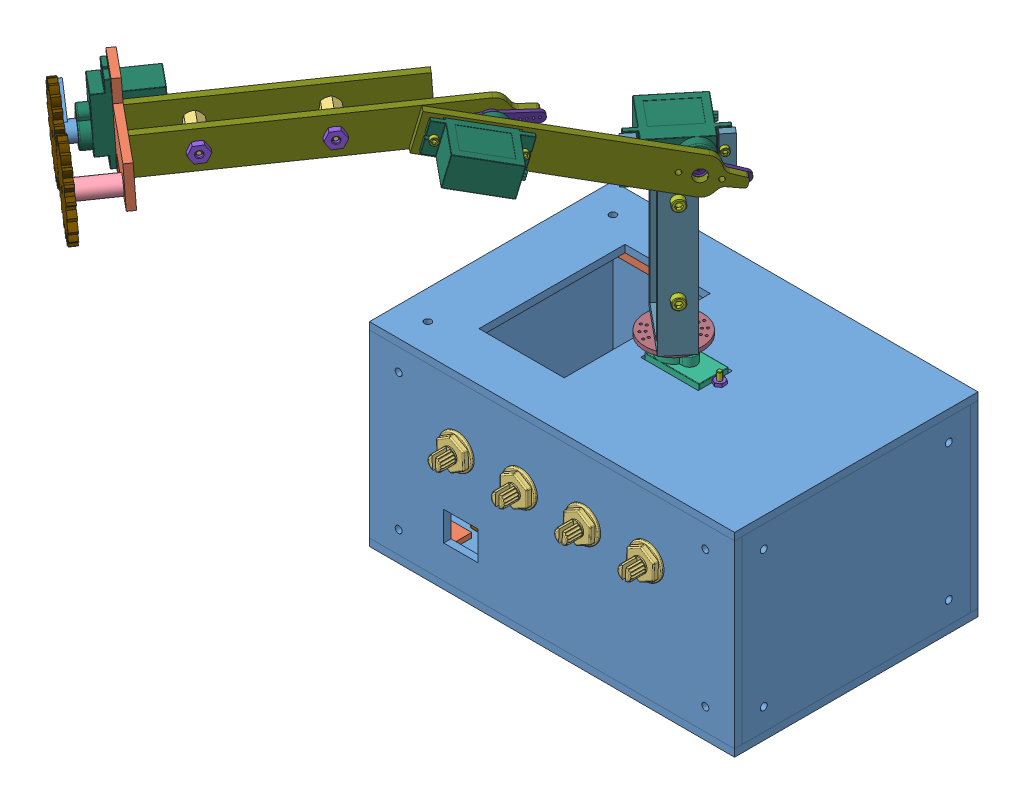
SolidWorks assembly baseAssem, configuration Default. Lengths in mm.
Overall size (216.34 190.48 226.77).
72 component instances, 22 part files, 144 mates.
Components (placement in the parent):
- base-2: base [bottom] at (55.526 72.3187 118.4129) size (150 3 100)
- base-3: base [top] at (55.526 149.3187 118.4129) size (150 3 100)
- base-4: base [right] at (55.526 112.3187 165.4129) x (1 0 0) z (0 -1 0) size (150 3 74)
- base-5: base [left] at (55.526 112.3187 68.4129) x (-1 0 0) z (0 1 0) size (150 3 74)
- base-6: base [back] at (-16.474 112.3187 118.4129) x (0 0 -1) z (0 1 0) size (94 3 74)
- corner-1: corner [Default] at (-7.474 131.3187 156.4129) x (0 0 1) z (-1 0 0) size (18 18 18)
- corner-3: corner [Default] at (1.526 84.3187 156.4129) x (0 0 1) z (0 -1 0) size (18 18 18)
- corner-4: corner [Default] at (-7.474 93.3187 80.4129) x (0 0 -1) z (-1 0 0) size (18 18 18)
- corner-8: corner [Default] at (-7.474 140.3187 89.4129) x (0 1 0) z (-1 0 0) size (18 18 18)
- base-7: base [front] at (127.526 112.3187 118.4129) x (0 0 1) z (0 1 0) size (94 3 74)
- Panel Mount 10k Potentiometer-1: Panel Mount 10k Potentiometer [Default] at (16.526 124.3187 161.9129) x (0 0 1) z (-0.999338 -0.036385 0) size (23.57 25.5 17)
- Panel Mount 10k Potentiometer-2: Panel Mount 10k Potentiometer [Default] at (42.526 124.3187 161.9129) x (0 0 1) z (-0.999906 0.013744 0) size (23.57 25.5 17)
- Panel Mount 10k Potentiometer-3: Panel Mount 10k Potentiometer [Default] at (68.526 124.3187 161.9129) x (0 0 1) z (-0.998975 0.045273 0) size (23.57 25.5 17)
- Panel Mount 10k Potentiometer-4: Panel Mount 10k Potentiometer [Default] at (94.526 124.3187 161.9129) x (0 0 1) z (-0.999254 0.038611 0) size (23.57 25.5 17)
- Panel Mount LED-1: Panel Mount LED [Default] at (50.526 112.3187 78.4129) x (0.923439 -0.383746 0) z (0.383746 0.923439 0) size (11.13 16 10.04)
- Panel Mount SPDT-1: Panel Mount SPDT [Default] at (70.526 112.3187 83.8429) x (-1 0 0) z (0 -1 0) size (8 31.74 12.7)
- Micro Servo FS90R Continuous - Copy-1: Micro Servo FS90R Continuous - Copy [Valor predeterminado] at (60.771 147.3187 118.4129) size (32 29 12)
- socket head cap screw_ai-25: socket head cap screw_ai [HX-SHCS 0.073-72x0.375x0.375-N] at (47.146 145.4645 118.4129) x (0 1 0) z (-0.929485 0 -0.368859) size (11.38 3 3)
- socket head cap screw_ai-26: socket head cap screw_ai [HX-SHCS 0.073-72x0.375x0.375-N] at (74.396 145.4645 118.4129) x (0 1 0) z (-0.215216 0 0.976566) size (11.38 3 3)
- machine screw nut hex_ai-1: machine screw nut hex_ai [MSHXNUT 0.073-72-S-N] at (74.396 153.5887 118.4129) x (-0.435877 0 0.900006) z (0 1 0) size (3.96 4.58 1.27)
- machine screw nut hex_ai-2: machine screw nut hex_ai [MSHXNUT 0.073-72-S-N] at (47.146 153.5887 118.4129) x (0.391838 0 0.920034) z (0 1 0) size (3.96 4.58 1.27)
- ArduinoUno-1: ArduinoUno [Default] at (29.676 88.0187 119.4129) x (0 0 -1) z (1 0 0) size (74.8 12.1 53.3)
- Arduino Prototyping Shield-1: Arduino Prototyping Shield [Default] at (30.976 97.6187 118.1031) x (0 0 1) z (-1 0 0) size (68 18.92 56)
- MiniBreadboard-Simple-1: MiniBreadboard-Simple [Default] at (30.276 99.2487 122.3031) x (-1 0 0) z (0 0 -1) size (34.6 8.15 45.6)
- 25x.5 Aluminum Hex Female Female Standoff-1: 25x.5 Aluminum Hex Female Female Standoff [Default] at (48.726 81.6687 86.0129) x (0.839669 0 0.543098) z (0 1 0) size (6.35 8.06 12.7)
- 25x.5 Aluminum Hex Female Female Standoff-2: 25x.5 Aluminum Hex Female Female Standoff [Default] at (5.526 81.6687 136.8129) x (0.967511 0 -0.252828) z (0 -1 0) size (6.35 8.06 12.7)
- 25x.5 Aluminum Hex Female Female Standoff-3: 25x.5 Aluminum Hex Female Female Standoff [Default] at (20.826 81.6687 86.0129) x (0.85033 0 -0.52625) z (0 1 0) size (6.35 8.06 12.7)
- 25x.5 Aluminum Hex Female Female Standoff-4: 25x.5 Aluminum Hex Female Female Standoff [Default] at (53.826 81.6687 138.4129) x (0.990977 0 0.134031) z (0 -1 0) size (6.35 8.06 12.7)
- bottom servo assem-1: bottom servo assem [Default] at (59.6282 148.85 98.1163) x (0.770206 0 0.637795) z (-0.637795 0 0.770206) size (36.89 82.63 34.06) (flexible)
  - Micro Servo Horn Round-1: Micro Servo Horn Round [Default] at (9.7817 11.4557 18.2521) size (23.65 4.35 23.65)
  - bottom servo arm-1: bottom servo arm [Default] at (9.7714 16.0686 18.2394) x (0.999997 0 -0.002296) z (-0.002296 0 -0.999997) size (26 78 34)
  - socket head cap screw_ai-1: socket head cap screw_ai [HX-SHCS 0.112-40x0.5x0.5-N] at (25.6162 33.0686 18.203) x (-0.999997 0 0.002296) z (-0.000065 -0.999594 -0.028493) size (15.54 4.65 4.65)
  - socket head cap screw_ai-2: socket head cap screw_ai [HX-SHCS 0.112-40x0.5x0.5-N] at (25.6162 68.0686 18.203) x (-0.999997 0 0.002296) z (-0.000065 -0.999594 -0.028493) size (15.54 4.65 4.65)
  - 25x.5 Aluminum Hex Female Female Standoff-1: 25x.5 Aluminum Hex Female Female Standoff [Default] at (9.7714 68.0686 18.2394) x (-0.002123 -0.380865 -0.924628) z (0.999997 0 -0.002296) size (6.35 8.06 12.7)
  - 25x.5 Aluminum Hex Female Female Standoff-2: 25x.5 Aluminum Hex Female Female Standoff [Default] at (9.7714 33.0686 18.2394) x (-0.001939 -0.535745 -0.844378) z (0.999997 0 -0.002296) size (6.35 8.06 12.7)
  - Micro Servo SG92R 180-1: Micro Servo SG92R 180 [Valor predeterminado] at (17.7714 85.5949 18.221) x (0.002296 0 0.999997) z (0 1 0) size (32 29 12)
  - socket head cap screw_ai-3: socket head cap screw_ai [HX-SHCS 0.112-40x0.5x0.5-N] at (-6.0733 68.0686 18.2758) x (0.999997 0 -0.002296) z (-0.000307 -0.991051 -0.133483) size (15.54 4.65 4.65)
  - socket head cap screw_ai-4: socket head cap screw_ai [HX-SHCS 0.112-40x0.5x0.5-N] at (-6.0733 33.0686 18.2758) x (0.999997 0 -0.002296) z (-0.000307 -0.991051 -0.133483) size (15.54 4.65 4.65)
  - socket head cap screw_ai-5: socket head cap screw_ai [HX-SHCS 0.073-72x0.375x0.375-N] at (24.6569 85.5949 31.8303) x (-0.999997 0 0.002296) z (-0.002286 -0.096256 -0.995354) size (11.38 3 3)
  - socket head cap screw_ai-6: socket head cap screw_ai [HX-SHCS 0.073-72x0.375x0.375-N] at (24.5943 85.5949 4.5803) x (-0.999997 0 0.002296) z (0.000316 0.990504 0.137486) size (11.38 3 3)
  - machine screw nut hex_ai-3: machine screw nut hex_ai [MSHXNUT 0.073-72-S-N] at (17.8027 85.5949 31.846) x (-0.002207 -0.276755 -0.960938) z (0.999997 0 -0.002296) size (3.96 4.58 1.27)
  - machine screw nut hex_ai-4: machine screw nut hex_ai [MSHXNUT 0.073-72-S-N] at (17.7401 85.5949 4.5961) x (-0.001605 -0.71523 -0.698887) z (0.999997 0 -0.002296) size (3.96 4.58 1.27)
- machine screw nut hex_ai-3: machine screw nut hex_ai [MSHXNUT 0.073-72-S-N] at (51.25 166.1887 114.8762) x (1 0 0) z (0 1 0) size (3.96 4.58 1.27)
- machine screw nut hex_ai-4: machine screw nut hex_ai [MSHXNUT 0.073-72-S-N] at (59.7924 166.1887 121.917) x (1 0 0) z (0 1 0) size (3.96 4.58 1.27)
- socket head cap screw_ai-27: socket head cap screw_ai [HX-SHCS 0.073-72x0.375x0.375-N] at (59.7924 158.4516 121.917) x (0 1 0) z (0.579913 0 0.814678) size (11.38 3 3)
- socket head cap screw_ai-28: socket head cap screw_ai [HX-SHCS 0.073-72x0.375x0.375-N] at (51.25 158.4516 114.8762) x (0 1 0) z (-0.855432 0 -0.517915) size (11.38 3 3)
- corner-11: corner [Default] at (109.526 140.3187 80.4129) x (0 1 0) z (0 0 -1) size (18 18 18)
- corner-12: corner [Default] at (109.526 84.3187 156.4129) x (0 -1 0) z (0 0 1) size (18 18 18)
- corner-13: corner [Default] at (118.526 131.3187 156.4129) size (18 18 18)
- corner-14: corner [Default] at (109.526 84.3187 80.4129) x (0 0 -1) z (0 -1 0) size (18 18 18)
- second servo arm-1: second servo arm [Default] at (54.5607 243.1953 155.2982) x (-0.616355 0.246769 0.747805) z (0.156951 0.969074 -0.190424) size (100 3 15)
- Micro Servo Horn Double Arm-1: Micro Servo Horn Double Arm [Default] at (75.1551 234.4449 127.7758) x (-0.616511 0.245803 0.747994) z (0.156336 0.96932 -0.189678) size (32.23 4.23 7.24)
- Micro Servo SG92R 180-1: Micro Servo SG92R 180 [Valor predeterminado] at (38.9269 250.9994 182.1276) x (-0.616355 0.246769 0.747805) z (-0.156951 -0.969074 0.190424) size (32 29 12)
- socket head cap screw_ai-29: socket head cap screw_ai [HX-SHCS 0.073-72x0.375x0.375-N] at (32.114 254.2999 193.3088) x (-0.771669 0 -0.636024) z (0.582813 0.400408 -0.707109) size (11.38 3 3)
- machine screw nut hex_ai-5: machine screw nut hex_ai [MSHXNUT 0.073-72-S-N] at (26.8248 254.2999 188.9494) x (-0.062279 -0.995194 0.075561) z (0.771669 0 0.636024) size (3.96 4.58 1.27)
- socket head cap screw_ai-30: socket head cap screw_ai [HX-SHCS 0.073-72x0.375x0.375-N] at (48.9096 247.5755 172.9311) x (-0.771669 0 -0.636024) z (-0.301428 -0.880565 0.365714) size (11.38 3 3)
- machine screw nut hex_ai-6: machine screw nut hex_ai [MSHXNUT 0.073-72-S-N] at (43.6205 247.5755 168.5717) x (0.611181 -0.276759 -0.741527) z (0.771669 0 0.636024) size (3.96 4.58 1.27)
- Micro Servo Horn Double Arm-2: Micro Servo Horn Double Arm [Default] at (32.0414 249.7038 169.8594) x (-0.634939 -0.058392 0.770352) z (0.037139 -0.998294 -0.04506) size (32.23 4.23 7.24)
- second servo arm-3: second servo arm [third servo arm] at (8.2998 247.593 196.1284) x (-0.634902 -0.059388 0.770307) z (0.037772 -0.998235 -0.045828) size (120 3 15)
- root_gear-1: root_gear [other robot gear] at (-66.1465 236.144 247.7741) x (-0.605578 0.657397 -0.448447) z (0.479765 0.751201 0.453346) size (32.73 3 32.73)
- Micro Servo Horn Single Arm-1: Micro Servo Horn Single Arm [Default] at (-65.1225 236.2398 246.5317) x (0.605578 -0.657397 0.448447) z (-0.479765 -0.751201 -0.453346) size (19.74 4.23 7.24)
- Micro Servo SG92R 180-2: Micro Servo SG92R 180 [Valor predeterminado] at (-56.9933 242.2594 236.6688) x (-0.037772 0.998235 0.045828) z (0.771669 0 0.636024) size (32 29 12)
- second servo arm-4: second servo arm [fourth servo supporter] at (-6.1304 247.593 184.2348) x (-0.634902 -0.059388 0.770307) z (-0.037772 0.998235 0.045828) size (90 3 15)
- socket head cap screw_ai-31: socket head cap screw_ai [HX-SHCS 0.112-40x0.375x0.375-N] at (-14.6746 246.9991 190.1285) x (0.771669 0 0.636024) z (0.08876 -0.990214 -0.10769) size (12.37 4.65 4.65)
- socket head cap screw_ai-34: socket head cap screw_ai [HX-SHCS 0.112-40x0.375x0.375-N] at (-40.0707 244.6236 220.9407) x (0.771669 0 0.636024) z (0.384692 -0.796349 -0.466735) size (12.37 4.65 4.65)
- gear support-1: gear support [Default] at (-43.3206 242.4376 244.0572) x (0.771669 0 0.636024) z (0.037772 -0.998235 -0.045828) size (46 3 35)
- 25x.5 Aluminum Hex Male Female Standoff-1: 25x.5 Aluminum Hex Male Female Standoff [Default] at (-30.6604 244.6236 228.6969) x (-0.245877 0.922254 0.298315) z (-0.771669 0 -0.636024) size (6.35 8.06 17.4)
- 25x.5 Aluminum Hex Male Female Standoff-2: 25x.5 Aluminum Hex Male Female Standoff [Default] at (-5.2643 246.9991 197.8846) x (-0.257451 0.914413 0.312358) z (-0.771669 0 -0.636024) size (6.35 8.06 17.4)
- machine screw nut hex_ai-7: machine screw nut hex_ai [MSHXNUT 0.112-40-S-N] at (1.9508 246.9991 203.8315) x (0.516896 0.582684 -0.627135) z (-0.771669 0 -0.636024) size (6.35 7.33 2.49)
- machine screw nut hex_ai-8: machine screw nut hex_ai [MSHXNUT 0.112-40-S-N] at (-23.4453 244.6236 234.6438) x (0.516896 0.582684 -0.627135) z (-0.771669 0 -0.636024) size (6.35 7.33 2.49)
- root_gear-2: root_gear [other robot gear] at (-43.3106 236.4934 266.6229) x (0.649947 0.497985 0.574091) z (0.417695 -0.86515 0.277573) size (32.73 3 32.73)
- 3D printed standoff-1: 3D printed standoff [Default] at (-43.3112 236.4933 266.6235) x (0.770009 0.032837 0.637188) z (-0.634902 -0.059388 0.770307) size (7 12.18 14.73)
Mates (geometry in assembly coordinates):
- Coincident1: coincident anti-aligned: plane of base-2 through (55.526 75.3187 118.4129) normal (0 1 0); plane of base-4 through (130.526 75.3187 168.4129) normal (0 -1 0)
- Coincident2: coincident aligned: line of base-2 through (-19.474 75.3187 168.4129) axis (1 0 0); line of base-4 through (-19.474 75.3187 168.4129) axis (1 0 0)
- Coincident3: coincident aligned: line of base-2 through (130.526 75.3187 168.4129) axis (0 0 -1); line of base-4 through (130.526 75.3187 168.4129) axis (0 0 -1)
- Coincident4: coincident anti-aligned: plane of base-2 through (55.526 75.3187 118.4129) normal (0 1 0); plane of base-5 through (-19.474 75.3187 71.4129) normal (0 -1 0)
- Coincident6: coincident anti-aligned: line of base-2 through (130.526 75.3187 68.4129) axis (-1 0 0); line of base-5 through (-19.474 75.3187 68.4129) axis (1 0 0)
- Coincident7: coincident aligned: line of base-2 through (130.526 75.3187 168.4129) axis (0 0 -1); line of base-5 through (130.526 75.3187 71.4129) axis (0 0 -1)
- Coincident12: coincident anti-aligned: plane of base-2 through (55.526 75.3187 118.4129) normal (0 1 0); plane of base-6 through (-19.474 75.3187 71.4129) normal (0 -1 0)
- Coincident13: coincident anti-aligned: plane of base-5 through (55.526 112.3187 71.4129) normal (0 0 1); plane of base-6 through (-19.474 149.3187 71.4129) normal (0 0 -1)
- Coincident14: coincident aligned: line of base-2 through (-19.474 75.3187 68.4129) axis (0 0 1); line of base-6 through (-19.474 75.3187 71.4129) axis (0 0 1)
- Coincident15: coincident anti-aligned: plane of base-3 through (55.526 149.3187 118.4129) normal (0 -1 0); plane of base-6 through (-19.474 149.3187 71.4129) normal (0 1 0)
- Coincident16: coincident anti-aligned: line of base-3 through (-19.474 149.3187 168.4129) axis (1 0 0); line of base-4 through (130.526 149.3187 168.4129) axis (-1 0 0)
- Coincident18: coincident anti-aligned: plane of base-4 through (55.526 112.3187 165.4129) normal (0 0 -1); plane of corner-1 through (-16.474 149.3187 165.4129) normal (0 0 1)
- Coincident19: coincident anti-aligned: plane of base-6 through (-16.474 112.3187 118.4129) normal (1 0 0); plane of corner-1 through (-16.474 149.3187 147.4129) normal (-1 0 0)
- Coincident20: coincident anti-aligned: plane of base-3 through (55.526 149.3187 118.4129) normal (0 -1 0); plane of corner-1 through (-7.474 149.3187 156.4129) normal (0 1 0)
- Coincident21: coincident anti-aligned: plane of base-5 through (55.526 112.3187 71.4129) normal (0 0 1); plane of corner-8 through (-7.474 140.3187 71.4129) normal (0 0 -1)
- Coincident22: coincident anti-aligned: plane of base-3 through (55.526 149.3187 118.4129) normal (0 -1 0); plane of corner-8 through (-16.474 149.3187 71.4129) normal (0 1 0)
- Coincident23: coincident anti-aligned: plane of base-6 through (-16.474 112.3187 118.4129) normal (1 0 0); plane of corner-8 through (-16.474 131.3187 71.4129) normal (-1 0 0)
- Coincident36: coincident anti-aligned: plane of base-5 through (55.526 112.3187 71.4129) normal (0 0 1); plane of corner-4 through (-16.474 75.3187 71.4129) normal (0 0 -1)
- Coincident37: coincident anti-aligned: plane of base-6 through (-16.474 112.3187 118.4129) normal (1 0 0); plane of corner-4 through (-16.474 75.3187 89.4129) normal (-1 0 0)
- Coincident38: coincident anti-aligned: plane of base-2 through (55.526 75.3187 118.4129) normal (0 1 0); plane of corner-4 through (-7.474 75.3187 80.4129) normal (0 -1 0)
- Coincident39: coincident anti-aligned: plane of base-6 through (-16.474 112.3187 118.4129) normal (1 0 0); plane of corner-3 through (-16.474 84.3187 156.4129) normal (-1 0 0)
- Coincident40: coincident anti-aligned: plane of base-2 through (55.526 75.3187 118.4129) normal (0 1 0); plane of corner-3 through (-16.474 75.3187 147.4129) normal (0 -1 0)
- Coincident41: coincident anti-aligned: plane of base-4 through (55.526 112.3187 165.4129) normal (0 0 -1); plane of corner-3 through (-16.474 75.3187 165.4129) normal (0 0 1)
- Coincident53: coincident anti-aligned: line of base-3 through (-19.474 149.3187 68.4129) axis (0 0 1); line of base-6 through (-19.474 149.3187 165.4129) axis (0 0 -1)
- Coincident63: coincident anti-aligned: plane of base-4 through (55.526 112.3187 165.4129) normal (0 0 -1); plane of base-7 through (130.526 149.3187 165.4129) normal (0 0 1)
- Coincident70: coincident anti-aligned: plane of base-4 through (55.526 112.3187 168.4129) normal (0 0 1); plane of Panel Mount 10k Potentiometer-1 through (16.526 124.3187 168.4129) normal (0 0 -1)
- Concentric1: concentric anti-aligned: cylinder of base-4 through (16.526 124.3187 158.4129) axis (0 0 1) radius 3.625; circle of Panel Mount 10k Potentiometer-1
- Coincident71: coincident anti-aligned: plane of base-4 through (55.526 112.3187 168.4129) normal (0 0 1); plane of Panel Mount 10k Potentiometer-2 through (42.526 124.3187 168.4129) normal (0 0 -1)
- Concentric2: concentric anti-aligned: circle of base-4; circle of Panel Mount 10k Potentiometer-2
- Coincident72: coincident anti-aligned: plane of base-4 through (55.526 112.3187 168.4129) normal (0 0 1); plane of Panel Mount 10k Potentiometer-3 through (68.526 124.3187 168.4129) normal (0 0 -1)
- Concentric3: concentric anti-aligned: cylinder of base-4 through (68.526 124.3187 158.4129) axis (0 0 1) radius 3.625; circle of Panel Mount 10k Potentiometer-3
- Coincident73: coincident anti-aligned: plane of base-4 through (55.526 112.3187 168.4129) normal (0 0 1); plane of Panel Mount 10k Potentiometer-4 through (94.526 124.3187 168.4129) normal (0 0 -1)
- Concentric4: concentric anti-aligned: cylinder of base-4 through (94.526 124.3187 158.4129) axis (0 0 1) radius 3.625; circle of Panel Mount 10k Potentiometer-4
- Coincident74: coincident anti-aligned: plane of base-5 through (55.526 112.3187 68.4129) normal (0 0 -1); plane of Panel Mount SPDT-1 through (74.526 114.6281 68.4129) normal (0 0 1)
- Concentric5: concentric anti-aligned: cylinder of base-5 through (70.526 112.3187 78.4129) axis (0 0 -1) radius 4; cylinder of Panel Mount SPDT-1 through (70.526 112.3187 66.4129) axis (0 0 1) radius 3.175
- Coincident75: coincident anti-aligned: plane of base-5 through (55.526 112.3187 68.4129) normal (0 0 -1); plane of Panel Mount LED-1 through (55.1623 110.392 68.4129) normal (0 0 1)
- Concentric6: concentric anti-aligned: cylinder of base-5 through (50.526 112.3187 78.4129) axis (0 0 -1) radius 4; cylinder of Panel Mount LED-1 through (50.526 112.3187 78.4129) axis (0 0 1) radius 3.937
- Coincident76: coincident anti-aligned: plane of base-3 through (55.526 149.3187 118.4129) normal (0 -1 0); plane of Micro Servo FS90R Continuous - Copy-1 through (74.396 149.3187 118.4129) normal (0 1 0)
- Concentric7: concentric anti-aligned: circle of base-3; circle of Micro Servo FS90R Continuous - Copy-1
- Concentric8: concentric anti-aligned: circle of base-3; circle of Micro Servo FS90R Continuous - Copy-1
- Concentric9: concentric anti-aligned: cylinder of base-3 through (74.396 142.3187 118.4129) axis (0 1 0) radius 1.25; cylinder of socket head cap screw_ai-26 through (74.396 113.7145 118.4129) axis (0 -1 0) radius 0.9271
- Coincident77: coincident anti-aligned: plane of Micro Servo FS90R Continuous - Copy-1 through (74.396 147.3187 118.4129) normal (0 -1 0); plane of socket head cap screw_ai-26 through (72.9325 147.3187 118.0904) normal (0 1 0)
- Concentric10: concentric anti-aligned: cylinder of base-3 through (47.146 142.3187 118.4129) axis (0 1 0) radius 1.25; cylinder of socket head cap screw_ai-25 through (47.146 113.7145 118.4129) axis (0 -1 0) radius 0.9271
- Coincident78: coincident anti-aligned: plane of Micro Servo FS90R Continuous - Copy-1 through (47.146 147.3187 118.4129) normal (0 -1 0); plane of socket head cap screw_ai-25 through (47.6988 147.3187 117.02) normal (0 1 0)
- Concentric11: concentric anti-aligned: cylinder of socket head cap screw_ai-26 through (74.396 113.7145 118.4129) axis (0 -1 0) radius 0.9271; cylinder of machine screw nut hex_ai-1 through (74.396 152.3187 118.4129) axis (0 1 0) radius 0.7556
- Coincident79: coincident anti-aligned: plane of base-3 through (55.526 152.3187 118.4129) normal (0 1 0); plane of machine screw nut hex_ai-1 through (76.1231 152.3187 114.8468) normal (0 -1 0)
- Concentric12: concentric anti-aligned: cylinder of socket head cap screw_ai-25 through (47.146 113.7145 118.4129) axis (0 -1 0) radius 0.9271; cylinder of machine screw nut hex_ai-2 through (47.146 152.3187 118.4129) axis (0 1 0) radius 0.7556
- Coincident80: coincident anti-aligned: plane of base-3 through (55.526 152.3187 118.4129) normal (0 1 0); plane of machine screw nut hex_ai-2 through (45.5934 152.3187 114.7674) normal (0 -1 0)
- Coincident82: coincident anti-aligned: plane of Arduino Prototyping Shield-1 through (2.976 99.2487 152.1031) normal (0 1 0); plane of MiniBreadboard-Simple-1 through (12.976 99.2487 99.5031) normal (0 -1 0)
- Parallel3: parallel aligned: line of Arduino Prototyping Shield-1 through (2.976 99.2487 152.1031) axis (1 0 0); line of MiniBreadboard-Simple-1 through (12.976 99.2487 145.1031) axis (1 0 0)
- Distance1: distance = 7 mm: line of MiniBreadboard-Simple-1 through (12.976 99.2487 145.1031) axis (1 0 0); line of Arduino Prototyping Shield-1 through (2.976 99.2487 152.1031) axis (1 0 0)
- Distance2: distance = 10 mm: line of MiniBreadboard-Simple-1 through (12.976 99.2487 99.5031) axis (0 0 1); line of Arduino Prototyping Shield-1 through (2.976 99.2487 87.9631) axis (0 0 1)
- Coincident86: coincident anti-aligned: plane of ArduinoUno-1 through (6.676 97.6187 129.9131) normal (0 1 0); plane of Arduino Prototyping Shield-1 through (2.976 97.6187 152.1031) normal (0 -1 0)
- Width1: width anti-aligned: plane of Arduino Prototyping Shield-1 through (5.676 88.8687 89.0131) normal (1 0 0); plane of ArduinoUno-1 through (5.176 88.8687 89.0131) normal (-1 0 0); plane of Arduino Prototyping Shield-1 through (5.926 97.6187 89.7631) normal (-1 0 0); plane of ArduinoUno-1 through (4.926 97.6187 89.7631) normal (1 0 0)
- Width2: width anti-aligned: plane of Arduino Prototyping Shield-1 through (5.176 88.8687 89.0131) normal (0 0 -1); plane of ArduinoUno-1 through (5.176 88.8687 89.5131) normal (0 0 1); plane of Arduino Prototyping Shield-1 through (4.926 97.6187 88.7631) normal (0 0 1); plane of ArduinoUno-1 through (4.926 97.6187 89.7631) normal (0 0 -1)
- Concentric16: concentric aligned: circle of base-2; circle of 25x.5 Aluminum Hex Female Female Standoff-1
- Coincident87: coincident anti-aligned: plane of base-2 through (55.526 75.3187 118.4129) normal (0 1 0); plane of 25x.5 Aluminum Hex Female Female Standoff-1 through (48.726 75.3187 86.0129) normal (0 -1 0)
- Concentric17: concentric aligned: circle of base-2; circle of 25x.5 Aluminum Hex Female Female Standoff-3
- Coincident88: coincident anti-aligned: plane of base-2 through (55.526 75.3187 118.4129) normal (0 1 0); plane of 25x.5 Aluminum Hex Female Female Standoff-3 through (20.826 75.3187 86.0129) normal (0 -1 0)
- Concentric18: concentric anti-aligned: circle of base-2; circle of 25x.5 Aluminum Hex Female Female Standoff-2
- Coincident89: coincident anti-aligned: plane of base-2 through (55.526 75.3187 118.4129) normal (0 1 0); plane of 25x.5 Aluminum Hex Female Female Standoff-2 through (5.526 75.3187 136.8129) normal (0 -1 0)
- Concentric19: concentric anti-aligned: circle of base-2; circle of 25x.5 Aluminum Hex Female Female Standoff-4
- Coincident91: coincident anti-aligned: plane of base-2 through (55.526 75.3187 118.4129) normal (0 1 0); plane of 25x.5 Aluminum Hex Female Female Standoff-4 through (53.826 75.3187 138.4129) normal (0 -1 0)
- Parallel5: parallel aligned: plane of base-2 through (55.526 72.3187 118.4129) normal (0 -1 0); plane of Panel Mount SPDT-1 through (73.956 105.9687 74.9529) normal (0 -1 0)
- Concentric20: concentric aligned: circle of ArduinoUno-1; circle of 25x.5 Aluminum Hex Female Female Standoff-3
- Concentric21: concentric aligned: circle of ArduinoUno-1; circle of 25x.5 Aluminum Hex Female Female Standoff-1
- Coincident93: coincident anti-aligned: plane of ArduinoUno-1 through (3.026 88.0187 86.4129) normal (0 -1 0); plane of 25x.5 Aluminum Hex Female Female Standoff-3 through (20.826 88.0187 86.0129) normal (0 1 0)
- Concentric22: concentric anti-aligned: cylinder of Micro Servo FS90R Continuous - Copy-1 through (55.521 160.3187 118.4129) axis (0 -1 0) radius 2.25; cone of bottom servo assem-1/Micro Servo Horn Round-1 through (55.521 157.8187 118.4129) axis (0 1 0)
- Coincident94: coincident anti-aligned: plane of Micro Servo FS90R Continuous - Copy-1 through (55.521 157.8187 118.4129) normal (0 1 0); plane of bottom servo assem-1/Micro Servo Horn Round-1 through (55.521 157.8187 118.4129) normal (0 -1 0)
- Concentric23: concentric anti-aligned: cylinder of bottom servo assem-1/bottom servo arm-1 through (59.7924 154.9187 121.917) axis (0 1 0) radius 1; cylinder of socket head cap screw_ai-27 through (59.7924 126.7016 121.917) axis (0 -1 0) radius 0.9271
- Coincident95: coincident anti-aligned: plane of bottom servo assem-1/Micro Servo Horn Round-1 through (55.521 160.3058 118.4129) normal (0 -1 0); plane of socket head cap screw_ai-27 through (58.5715 160.3058 122.7861) normal (0 1 0)
- Concentric24: concentric anti-aligned: circle of bottom servo assem-1/bottom servo arm-1; cylinder of socket head cap screw_ai-28 through (51.25 126.7016 114.8762) axis (0 -1 0) radius 0.9271
- Coincident96: coincident anti-aligned: plane of bottom servo assem-1/Micro Servo Horn Round-1 through (55.521 160.3058 118.4129) normal (0 -1 0); plane of socket head cap screw_ai-28 through (52.0262 160.3058 113.5943) normal (0 1 0)
- Concentric25: concentric anti-aligned: cylinder of machine screw nut hex_ai-4 through (59.7924 164.9187 121.917) axis (0 1 0) radius 0.7556; cylinder of socket head cap screw_ai-27 through (59.7924 126.7016 121.917) axis (0 -1 0) radius 0.9271
- Coincident97: coincident anti-aligned: plane of bottom servo assem-1/bottom servo arm-1 through (55.5212 164.9187 118.3966) normal (0 1 0); plane of machine screw nut hex_ai-4 through (55.83 164.9187 121.917) normal (0 -1 0)
- Concentric26: concentric anti-aligned: cylinder of machine screw nut hex_ai-3 through (51.25 164.9187 114.8762) axis (0 1 0) radius 0.7556; cylinder of socket head cap screw_ai-28 through (51.25 126.7016 114.8762) axis (0 -1 0) radius 0.9271
- Coincident98: coincident anti-aligned: plane of bottom servo assem-1/bottom servo arm-1 through (55.5212 164.9187 118.3966) normal (0 1 0); plane of machine screw nut hex_ai-3 through (47.2876 164.9187 114.8762) normal (0 -1 0)
- Coincident99: coincident anti-aligned: plane of base-2 through (55.526 75.3187 118.4129) normal (0 1 0); plane of base-7 through (130.526 75.3187 165.4129) normal (0 -1 0)
- Coincident100: coincident aligned: plane of base-4 through (130.526 75.3187 168.4129) normal (1 0 0); plane of base-7 through (130.526 112.3187 118.4129) normal (1 0 0)
- Coincident101: coincident anti-aligned: plane of base-7 through (127.526 112.3187 118.4129) normal (-1 0 0); plane of corner-13 through (127.526 149.3187 165.4129) normal (1 0 0)
- Coincident102: coincident anti-aligned: plane of base-4 through (55.526 112.3187 165.4129) normal (0 0 -1); plane of corner-13 through (109.526 149.3187 165.4129) normal (0 0 1)
- Coincident103: coincident anti-aligned: plane of base-3 through (55.526 149.3187 118.4129) normal (0 -1 0); plane of corner-13 through (118.526 149.3187 156.4129) normal (0 1 0)
- Coincident104: coincident anti-aligned: plane of base-4 through (55.526 112.3187 165.4129) normal (0 0 -1); plane of corner-12 through (127.526 93.3187 165.4129) normal (0 0 1)
- Coincident105: coincident anti-aligned: plane of base-7 through (127.526 112.3187 118.4129) normal (-1 0 0); plane of corner-12 through (127.526 84.3187 156.4129) normal (1 0 0)
- Coincident106: coincident anti-aligned: plane of base-2 through (55.526 75.3187 118.4129) normal (0 1 0); plane of corner-12 through (127.526 75.3187 165.4129) normal (0 -1 0)
- Coincident107: coincident anti-aligned: plane of base-5 through (55.526 112.3187 71.4129) normal (0 0 1); plane of corner-11 through (127.526 131.3187 71.4129) normal (0 0 -1)
- Coincident108: coincident anti-aligned: plane of base-7 through (127.526 112.3187 118.4129) normal (-1 0 0); plane of corner-11 through (127.526 140.3187 80.4129) normal (1 0 0)
- Coincident109: coincident anti-aligned: plane of base-3 through (55.526 149.3187 118.4129) normal (0 -1 0); plane of corner-11 through (127.526 149.3187 71.4129) normal (0 1 0)
- Coincident110: coincident anti-aligned: plane of base-2 through (55.526 75.3187 118.4129) normal (0 1 0); plane of corner-14 through (127.526 75.3187 89.4129) normal (0 -1 0)
- Coincident112: coincident anti-aligned: plane of base-5 through (55.526 112.3187 71.4129) normal (0 0 1); plane of corner-14 through (127.526 75.3187 71.4129) normal (0 0 -1)
- Coincident113: coincident anti-aligned: plane of base-7 through (127.526 112.3187 118.4129) normal (-1 0 0); plane of corner-14 through (127.526 84.3187 80.4129) normal (1 0 0)
- Concentric34: concentric aligned: cylinder of bottom servo assem-1/Micro Servo SG92R 180-1 through (75.0654 234.4449 127.7019) axis (-0.771669 0 -0.636024) radius 2.25; cylinder of Micro Servo Horn Double Arm-1 through (74.9395 234.4449 127.5981) axis (-0.771669 0 -0.636024) radius 2.286
- Coincident126: coincident anti-aligned: plane of bottom servo assem-1/Micro Servo SG92R 180-1 through (73.1362 234.4449 126.1118) normal (0.771669 0 0.636024); plane of Micro Servo Horn Double Arm-1 through (73.1362 234.4449 126.1118) normal (-0.771669 0 -0.636024)
- Coincident127: coincident anti-aligned: plane of second servo arm-1 through (54.5607 243.1953 155.2982) normal (-0.771669 0 -0.636024); plane of Micro Servo Horn Double Arm-1 through (76.3997 234.4449 128.8016) normal (0.771669 0 0.636024)
- Concentric35: concentric aligned: circle of second servo arm-1; circle of Micro Servo Horn Double Arm-1
- Concentric37: concentric aligned: circle of second servo arm-1; circle of Micro Servo Horn Double Arm-1
- Parallel6: parallel aligned: plane of second servo arm-1 through (86.5164 223.5888 121.2442) normal (-0.156951 -0.969074 0.190424); plane of Micro Servo SG92R 180-1 through (38.0009 245.2818 183.2511) normal (-0.156951 -0.969074 0.190424)
- Coincident130: coincident anti-aligned: plane of second servo arm-1 through (56.8758 243.1953 157.2062) normal (0.771669 0 0.636024); plane of Micro Servo SG92R 180-1 through (28.9857 254.3616 191.0444) normal (-0.771669 0 -0.636024)
- Width5: width aligned: plane of second servo arm-1 through (88.8706 238.1249 118.3878) normal (0.156951 0.969074 -0.190424); plane of Micro Servo SG92R 180-1 through (86.5164 223.5888 121.2442) normal (-0.156951 -0.969074 0.190424); plane of second servo arm-1 through (39.8529 256.7169 181.0041) normal (0.156951 0.969074 -0.190424); plane of Micro Servo SG92R 180-1 through (38.0009 245.2818 183.2511) normal (-0.156951 -0.969074 0.190424)
- Width6: width anti-aligned: plane of second servo arm-1 through (21.3275 247.6308 184.6132) normal (0.616355 -0.246769 -0.747805); plane of Micro Servo SG92R 180-1 through (35.9659 241.77 166.8529) normal (-0.616355 0.246769 0.747805); plane of second servo arm-1 through (45.2813 259.59 199.5742) normal (-0.616355 0.246769 0.747805); plane of Micro Servo SG92R 180-1 through (59.1493 254.0377 182.7486) normal (0.616355 -0.246769 -0.747805)
- Concentric41: concentric anti-aligned: cylinder of second servo arm-1 through (34.5415 254.2999 195.3096) axis (-0.771669 0 -0.636024) radius 1; cylinder of socket head cap screw_ai-29 through (56.6145 254.2999 213.5026) axis (0.771669 0 0.636024) radius 0.9271
- Coincident135: coincident anti-aligned: plane of Micro Servo SG92R 180-1 through (30.529 254.3616 192.3164) normal (0.771669 0 0.636024); plane of socket head cap screw_ai-29 through (30.3015 255.6731 192.5925) normal (-0.771669 0 -0.636024)
- Concentric42: concentric anti-aligned: cylinder of second servo arm-1 through (51.3371 247.5755 174.9319) axis (-0.771669 0 -0.636024) radius 1; cylinder of socket head cap screw_ai-30 through (73.4101 247.5755 193.1249) axis (0.771669 0 0.636024) radius 0.9271
- Coincident136: coincident anti-aligned: plane of Micro Servo SG92R 180-1 through (47.3247 247.6372 171.9388) normal (0.771669 0 0.636024); plane of socket head cap screw_ai-30 through (48.3181 246.8652 170.7335) normal (-0.771669 0 -0.636024)
- Concentric43: concentric aligned: cylinder of socket head cap screw_ai-29 through (56.6145 254.2999 213.5026) axis (0.771669 0 0.636024) radius 0.9271; cylinder of machine screw nut hex_ai-5 through (25.8448 254.2999 188.1416) axis (0.771669 0 0.636024) radius 0.7556
- Coincident137: coincident anti-aligned: plane of second servo arm-1 through (54.5607 243.1953 155.2982) normal (-0.771669 0 -0.636024); plane of machine screw nut hex_ai-5 through (27.0716 258.2433 188.65) normal (0.771669 0 0.636024)
- Concentric44: concentric aligned: cylinder of socket head cap screw_ai-30 through (73.4101 247.5755 193.1249) axis (0.771669 0 0.636024) radius 0.9271; cylinder of machine screw nut hex_ai-6 through (42.6404 247.5755 167.7639) axis (0.771669 0 0.636024) radius 0.7556
- Coincident138: coincident anti-aligned: plane of second servo arm-1 through (54.5607 243.1953 155.2982) normal (-0.771669 0 -0.636024); plane of machine screw nut hex_ai-6 through (41.1987 248.6721 171.5099) normal (0.771669 0 0.636024)
- Concentric45: concentric aligned: cylinder of Micro Servo SG92R 180-1 through (32.131 249.7038 169.9333) axis (0.771669 0 0.636024) radius 2.25; cylinder of Micro Servo Horn Double Arm-2 through (32.257 249.7038 170.0371) axis (0.771669 0 0.636024) radius 2.286
- Coincident139: coincident anti-aligned: plane of Micro Servo SG92R 180-1 through (34.0602 249.7038 171.5234) normal (-0.771669 0 -0.636024); plane of Micro Servo Horn Double Arm-2 through (34.0602 249.7038 171.5234) normal (0.771669 0 0.636024)
- Concentric48: concentric aligned: circle of Micro Servo Horn Double Arm-2; circle of second servo arm-3
- Concentric49: concentric anti-aligned: circle of Micro Servo Horn Double Arm-2; circle of second servo arm-3
- Coincident142: coincident anti-aligned: plane of Micro Servo Horn Double Arm-2 through (30.7967 249.7038 168.8336) normal (-0.771669 0 -0.636024); plane of second servo arm-3 through (8.2998 247.593 196.1284) normal (0.771669 0 0.636024)
- Coincident143: coincident anti-aligned: plane of root_gear-1 through (-66.1465 236.144 247.7741) normal (0.634902 0.059388 -0.770307); plane of Micro Servo Horn Single Arm-1 through (-66.1465 236.144 247.7741) normal (-0.634902 -0.059388 0.770307)
- Concentric50: concentric aligned: circle of root_gear-1; circle of Micro Servo Horn Single Arm-1
- Symmetric1: symmetric aligned: plane of root_gear-1 through (-66.1465 236.144 247.7741) normal (0.479765 0.751201 0.453346); plane of Micro Servo Horn Single Arm-1 through (-75.7579 244.1305 240.4679) normal (-0.527459 -0.695206 -0.488339); plane of Micro Servo Horn Single Arm-1 through (-73.9118 247.0211 242.2124) normal (0.428889 0.802211 0.415345)
- Concentric51: concentric aligned: cylinder of Micro Servo Horn Single Arm-1 through (-64.9451 236.2564 246.3165) axis (0.634902 0.059388 -0.770307) radius 2.286; cylinder of Micro Servo SG92R 180-2 through (-65.0487 236.2467 246.4422) axis (0.634902 0.059388 -0.770307) radius 2.25
- Coincident146: coincident anti-aligned: plane of Micro Servo Horn Single Arm-1 through (-63.4614 236.3951 244.5164) normal (0.634902 0.059388 -0.770307); plane of Micro Servo SG92R 180-2 through (-63.4614 236.3951 244.5164) normal (-0.634902 -0.059388 0.770307)
- Coincident148: coincident aligned: plane of second servo arm-3 through (37.4466 258.0491 156.0487) normal (-0.037772 0.998235 0.045828); plane of second servo arm-4 through (27.6464 258.0491 147.9712) normal (-0.037772 0.998235 0.045828)
- Coincident149: coincident aligned: plane of second servo arm-3 through (-36.1433 243.4358 250.0499) normal (-0.634902 -0.059388 0.770307); plane of second servo arm-4 through (-50.5735 243.4358 238.1562) normal (-0.634902 -0.059388 0.770307)
- Concentric53: concentric anti-aligned: cylinder of second servo arm-4 through (-25.5978 246.9991 181.1254) axis (0.771669 0 0.636024) radius 1.425; cylinder of socket head cap screw_ai-31 through (-39.1751 246.9991 169.9347) axis (-0.771669 0 -0.636024) radius 1.4224
- Coincident151: coincident anti-aligned: plane of second servo arm-4 through (-6.1304 247.593 184.2348) normal (-0.771669 0 -0.636024); plane of socket head cap screw_ai-31 through (-13.9431 246.6747 193.7137) normal (0.771669 0 0.636024)
- Concentric57: concentric anti-aligned: cylinder of second servo arm-4 through (-50.9938 244.6236 211.9377) axis (0.771669 0 0.636024) radius 1.425; cylinder of socket head cap screw_ai-34 through (-64.5712 244.6236 200.747) axis (-0.771669 0 -0.636024) radius 1.4224
- Coincident154: coincident anti-aligned: plane of second servo arm-4 through (-6.1304 247.593 184.2348) normal (-0.771669 0 -0.636024); plane of socket head cap screw_ai-34 through (-39.0526 243.2179 224.1783) normal (0.771669 0 0.636024)
- Coincident155: coincident anti-aligned: plane of second servo arm-4 through (-50.5735 243.4358 238.1562) normal (-0.634902 -0.059388 0.770307); plane of gear support-1 through (-43.3206 242.4376 244.0572) normal (0.634902 0.059388 -0.770307)
- Coincident156: coincident aligned: line of second servo arm-4 through (-48.5418 250.9226 240.408) axis (-0.771669 0 -0.636024); line of gear support-1 through (-25.8933 250.9226 259.0753) axis (-0.771669 0 -0.636024)
- Width9: width aligned: plane of gear support-1 through (-27.1559 233.7744 260.6072) normal (0.771669 0 0.636024); plane of gear support-1 through (-62.6527 233.7744 231.3501) normal (-0.771669 0 -0.636024); plane of second servo arm-3 through (8.2998 247.593 196.1284) normal (0.771669 0 0.636024); plane of second servo arm-4 through (-6.1304 247.593 184.2348) normal (-0.771669 0 -0.636024)
- Concentric58: concentric aligned: cylinder of socket head cap screw_ai-34 through (-64.5712 244.6236 200.747) axis (-0.771669 0 -0.636024) radius 1.4224; cylinder of 25x.5 Aluminum Hex Male Female Standoff-1 through (-35.5605 244.6236 224.6582) axis (-0.771669 0 -0.636024) radius 1.0287
- Coincident158: coincident anti-aligned: plane of second servo arm-4 through (-3.8154 247.593 186.1428) normal (0.771669 0 0.636024); plane of 25x.5 Aluminum Hex Male Female Standoff-1 through (-35.5605 244.6236 224.6582) normal (-0.771669 0 -0.636024)
- Coincident159: coincident anti-aligned: plane of second servo arm-3 through (5.9848 247.593 194.2203) normal (-0.771669 0 -0.636024); plane of 25x.5 Aluminum Hex Male Female Standoff-1 through (-25.7603 244.6236 232.7357) normal (0.771669 0 0.636024)
- Concentric59: concentric aligned: cylinder of socket head cap screw_ai-31 through (-39.1751 246.9991 169.9347) axis (-0.771669 0 -0.636024) radius 1.4224; circle of 25x.5 Aluminum Hex Male Female Standoff-2
- Coincident160: coincident anti-aligned: plane of second servo arm-4 through (-3.8154 247.593 186.1428) normal (0.771669 0 0.636024); plane of 25x.5 Aluminum Hex Male Female Standoff-2 through (-10.1644 246.9991 193.8459) normal (-0.771669 0 -0.636024)
- Concentric60: concentric anti-aligned: circle of second servo arm-3; cylinder of machine screw nut hex_ai-7 through (3.8716 246.9991 205.4147) axis (-0.771669 0 -0.636024) radius 1.1303
- Coincident161: coincident anti-aligned: plane of second servo arm-3 through (8.2998 247.593 196.1284) normal (0.771669 0 0.636024); plane of machine screw nut hex_ai-7 through (-1.3315 243.299 207.8138) normal (-0.771669 0 -0.636024)
- Coincident162: coincident anti-aligned: plane of second servo arm-3 through (8.2998 247.593 196.1284) normal (0.771669 0 0.636024); plane of machine screw nut hex_ai-8 through (-26.7275 240.9235 238.6261) normal (-0.771669 0 -0.636024)
- Concentric61: concentric anti-aligned: circle of second servo arm-3; cylinder of machine screw nut hex_ai-8 through (-21.5244 244.6236 236.2269) axis (-0.771669 0 -0.636024) radius 1.1303
- Coincident163: coincident anti-aligned: plane of Micro Servo SG92R 180-2 through (-52.4404 242.2594 240.4213) normal (0.771669 0 0.636024); plane of second servo arm-4 through (-6.1304 247.593 184.2348) normal (-0.771669 0 -0.636024)
- Coincident164: coincident anti-aligned: plane of Micro Servo SG92R 180-2 through (-57.5079 255.8604 237.2932) normal (0.634902 0.059388 -0.770307); plane of gear support-1 through (-45.2253 242.2594 246.3682) normal (-0.634902 -0.059388 0.770307)
- Coincident165: coincident aligned: plane of root_gear-1 through (-68.0512 235.9658 250.0851) normal (-0.634902 -0.059388 0.770307); plane of root_gear-2 through (-45.2153 236.3152 268.9338) normal (-0.634902 -0.059388 0.770307)
- GearMate1: gear = 26.25 : 26.25 mm: circle of root_gear-1; circle of root_gear-2
- Concentric62: concentric aligned: circle of root_gear-2; circle of 3D printed standoff-1
- Coincident168: coincident anti-aligned: plane of gear support-1 through (-45.2253 242.2594 246.3682) normal (-0.634902 -0.059388 0.770307); plane of 3D printed standoff-1 through (-34.1801 240.86 255.364) normal (0.634902 0.059388 -0.770307)
- Width11: width aligned: plane of Micro Servo SG92R 180-2 through (-51.8898 254.4398 221.0433) normal (-0.037772 0.998235 0.045828); plane of gear support-1 through (-51.0399 231.9795 220.0122) normal (0.037772 -0.998235 -0.045828); plane of Micro Servo SG92R 180-2 through (-27.798 250.7444 261.3863) normal (-0.037772 0.998235 0.045828); plane of gear support-1 through (-27.1559 233.7744 260.6072) normal (0.037772 -0.998235 -0.045828)
- Concentric63: concentric aligned: circle of gear support-1; circle of 3D printed standoff-1
